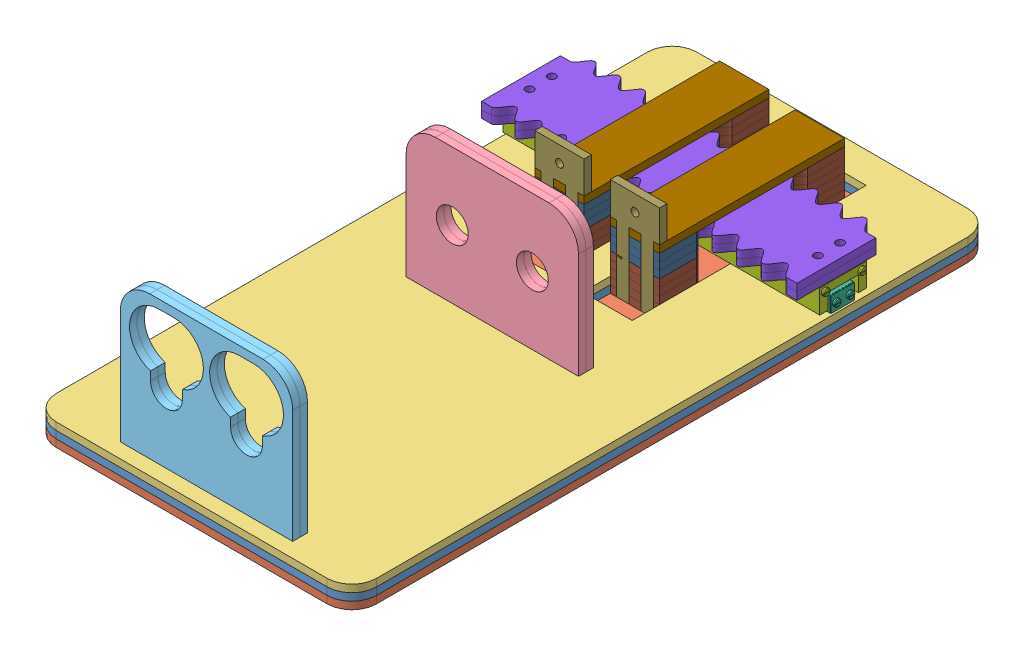
SolidWorks assembly whole-assembly, configuration Default. Lengths in mm.
Overall size (131.35 67 260).
51 component instances, 12 part files, 7 mates.
Components (placement in the parent):
- base-1: base [Default] at (-5.0912 -3.2088 4.8666) size (130 67 260)
  - tooth-track-middle-1: tooth-track-middle [Default] at (52.8281 64.7673 98.5849) size (130 3 260)
  - tooth-track-base-1: tooth-track-base [Default] at (52.8281 61.7673 98.5849) size (130 3 260)
  - tooth-track-2: tooth-track [Default] at (52.8281 67.7673 98.5849) size (130 3 260)
  - airpel-closed-1: airpel-closed [Default] at (52.8281 98.2673 170.5849) x (1 0 0) z (0 -1 0) size (70 3 61)
  - airpel-open-1: airpel-open [Default] at (52.8281 98.2673 286.5849) x (1 0 0) z (0 -1 0) size (70 3 64)
  - airpel-closed-2: airpel-closed [Default] at (52.8281 98.2673 173.5849) x (1 0 0) z (0 -1 0) size (70 3 61)
  - airpel-open-2: airpel-open [Default] at (52.8281 98.2673 289.5849) x (1 0 0) z (0 -1 0) size (70 3 64)
- linear_slide-1: linear_slide [Default] at (-16.5251 67.5585 103.4515) x (0 0 -1) z (1 0 0) size (37.42 16.41 131.35)
  - EA-5BH-1: EA-5BH [Default] at origin size (9.53 6.35 130.39)
  - EA-5CR-1: EA-5CR [Default] at (1.1141 0.889 -0.9629) size (19.05 9.53 130.39)
  - rack-5: rack [Default] at (1.1141 10.414 63.2991) x (0 0 -1) z (1 0 0) size (128 3 37.42)
  - rack-6: rack [Default] at (1.1141 13.414 63.2991) x (0 0 -1) z (1 0 0) size (128 3 37.42)
- piston-3: piston [Default] at (37.2581 43.6502 46.9655) size (20 40 75)
  - tooth-strip-1: tooth-strip [Default] at (26.7289 41.9083 55.3369) size (20 3 75)
  - tooth-piston-1: tooth-piston [Default] at (26.7289 35.9083 82.8369) x (-1 0 0) z (0 0 -1) size (20 3 20.01)
  - tooth-piston-2: tooth-piston [Default] at (26.7289 38.9083 82.8369) x (-1 0 0) z (0 0 -1) size (20 3 20.01)
  - tooth-end-1: tooth-end [Default] at (26.7289 38.9083 27.8369) size (20 3 20.01)
  - tooth-end-2: tooth-end [Default] at (26.7289 35.9083 27.8369) size (20 3 20.01)
  - tooth-piston-3: tooth-piston [Default] at (26.7289 32.9083 82.8369) x (-1 0 0) z (0 0 -1) size (20 3 20.01)
  - tooth-end-3: tooth-end [Default] at (26.7289 32.9083 27.8369) size (20 3 20.01)
  - stopper-1: stopper [Default] at (16.7289 17.9083 89.8369) x (1 0 0) z (0 -1 0) size (20 3 40)
  - tooth-end-4: tooth-end [Default] at (26.7289 29.9083 27.8369) size (20 3 20.01)
  - tooth-end-5: tooth-end [Default] at (26.7289 29.9083 82.8369) x (-1 0 0) z (0 0 -1) size (20 3 20.01)
  - tooth-end-6: tooth-end [Default] at (26.7289 26.9083 27.8369) size (20 3 20.01)
  - tooth-end-7: tooth-end [Default] at (26.7289 23.9083 27.8369) size (20 3 20.01)
  - tooth-end-8: tooth-end [Default] at (26.7289 26.9083 82.8369) x (-1 0 0) z (0 0 -1) size (20 3 20.01)
  - tooth-end-9: tooth-end [Default] at (26.7289 23.9083 82.8369) x (-1 0 0) z (0 0 -1) size (20 3 20.01)
  - tooth-end-10: tooth-end [Default] at (26.7289 20.9083 27.8369) size (20 3 20.01)
  - tooth-end-11: tooth-end [Default] at (26.7289 17.9083 27.8369) size (20 3 20.01)
  - tooth-end-12: tooth-end [Default] at (26.7289 20.9083 82.8369) x (-1 0 0) z (0 0 -1) size (20 3 20.01)
  - tooth-end-13: tooth-end [Default] at (26.7289 17.9083 82.8369) x (-1 0 0) z (0 0 -1) size (20 3 20.01)
- piston-4: piston [Default] at (4.7581 43.6502 45.0929) size (20 40 75)
  - tooth-strip-1: tooth-strip [Default] at (26.7289 41.9083 55.3369) size (20 3 75)
  - tooth-piston-1: tooth-piston [Default] at (26.7289 35.9083 82.8369) x (-1 0 0) z (0 0 -1) size (20 3 20.01)
  - tooth-piston-2: tooth-piston [Default] at (26.7289 38.9083 82.8369) x (-1 0 0) z (0 0 -1) size (20 3 20.01)
  - tooth-end-1: tooth-end [Default] at (26.7289 38.9083 27.8369) size (20 3 20.01)
  - tooth-end-2: tooth-end [Default] at (26.7289 35.9083 27.8369) size (20 3 20.01)
  - tooth-piston-3: tooth-piston [Default] at (26.7289 32.9083 82.8369) x (-1 0 0) z (0 0 -1) size (20 3 20.01)
  - tooth-end-3: tooth-end [Default] at (26.7289 32.9083 27.8369) size (20 3 20.01)
  - stopper-1: stopper [Default] at (16.7289 17.9083 89.8369) x (1 0 0) z (0 -1 0) size (20 3 40)
  - tooth-end-4: tooth-end [Default] at (26.7289 29.9083 27.8369) size (20 3 20.01)
  - tooth-end-5: tooth-end [Default] at (26.7289 29.9083 82.8369) x (-1 0 0) z (0 0 -1) size (20 3 20.01)
  - tooth-end-6: tooth-end [Default] at (26.7289 26.9083 27.8369) size (20 3 20.01)
  - tooth-end-7: tooth-end [Default] at (26.7289 23.9083 27.8369) size (20 3 20.01)
  - tooth-end-8: tooth-end [Default] at (26.7289 26.9083 82.8369) x (-1 0 0) z (0 0 -1) size (20 3 20.01)
  - tooth-end-9: tooth-end [Default] at (26.7289 23.9083 82.8369) x (-1 0 0) z (0 0 -1) size (20 3 20.01)
  - tooth-end-10: tooth-end [Default] at (26.7289 20.9083 27.8369) size (20 3 20.01)
  - tooth-end-11: tooth-end [Default] at (26.7289 17.9083 27.8369) size (20 3 20.01)
  - tooth-end-12: tooth-end [Default] at (26.7289 20.9083 82.8369) x (-1 0 0) z (0 0 -1) size (20 3 20.01)
  - tooth-end-13: tooth-end [Default] at (26.7289 17.9083 82.8369) x (-1 0 0) z (0 0 -1) size (20 3 20.01)
Mates (geometry in assembly coordinates):
- Coincident1: coincident anti-aligned: plane of base-1/tooth-track-2 through (47.7369 67.5585 103.4515) normal (0 1 0); plane of linear_slide-1/EA-5BH-1 through (-16.5251 67.5585 108.214) normal (0 -1 0)
- Concentric1: concentric anti-aligned: circle of base-1/tooth-track-2; circle of linear_slide-1/EA-5BH-1
- Concentric2: concentric aligned: circle of base-1/tooth-track-2; cylinder of linear_slide-1/EA-5BH-1 through (3.2369 67.241 103.4515) axis (0 1 0) radius 1.75
- Coincident4: coincident anti-aligned: plane of base-1/tooth-track-base-1 through (47.7369 61.5585 103.4515) normal (0 1 0); plane of piston-3/tooth-end-11 through (63.9869 61.5585 74.8024) normal (0 -1 0)
- Coincident5: coincident anti-aligned: plane of base-1/tooth-track-2 through (73.9869 64.5585 150.9515) normal (-1 0 0); plane of piston-3/tooth-end-7 through (73.9869 70.5585 84.8024) normal (1 0 0)
- Coincident6: coincident anti-aligned: plane of base-1/tooth-track-base-1 through (47.7369 61.5585 103.4515) normal (0 1 0); plane of piston-4/tooth-end-11 through (31.4869 61.5585 72.9298) normal (0 -1 0)
- Coincident7: coincident anti-aligned: plane of base-1/tooth-track-2 through (21.4869 64.5585 150.9515) normal (1 0 0); plane of piston-4/tooth-end-12 through (21.4869 67.5585 117.9298) normal (-1 0 0)
